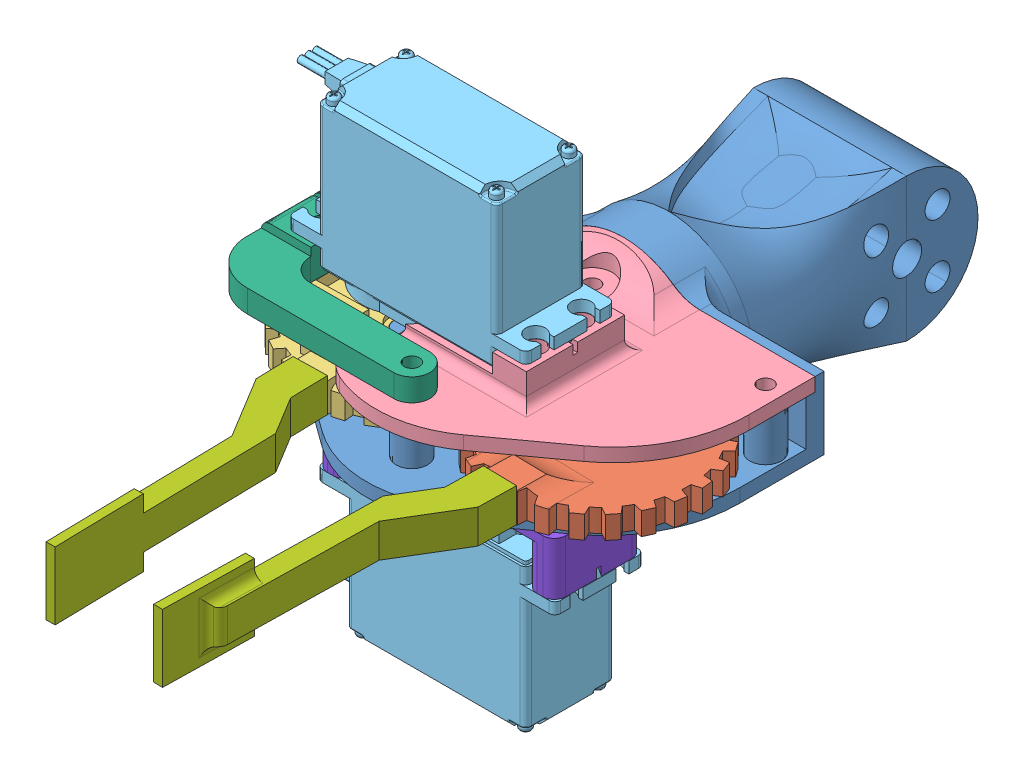
SolidWorks assembly pince, configuration Défaut. Lengths in mm.
Overall size (90.52 95.98 177.73).
10 component instances, 8 part files, 25 mates.
Components (placement in the parent):
- minisegmentServo-1: minisegmentServo [Default] at origin size (85 38 118.68)
- gearnoMot - Copie-2: gearnoMot - Copie [Défaut] at (21.5 5 72.8) x (-0.987503 0 -0.157599) z (-0.157599 0 0.987503) size (43.87 6.5 43.87)
- gearMot-1: gearMot [Défaut] at (-21.5 0 72.8) x (0.999762 0 -0.021829) z (0.021829 0 0.999762) size (43.87 7.5 43.44)
- toppince-1: toppince [Défaut] at (-0.0037 10 45.8) size (85 14.77 55)
- hs-422_sws-1: hs-422_sws [Default] at (-11.213 28.2654 82.706) x (0 0 -1) z (-1 0 0) size (19.81 42.14 58.23)
- supportServo-1: supportServo [Défaut] at (-38.5037 13 52.8) size (46.5 6.78 48)
- bout_pince-1: bout_pince [Défaut] at (21.5017 5 72.7083) x (-0.987503 0 -0.157599) z (-0.157599 0 0.987503) size (11.17 15 72.85)
- bout_pince-2: bout_pince [Défaut] at (-21.5028 2.5 72.6719) x (0.986994 0 -0.160756) z (0.160756 0 0.986994) size (11.17 15 72.85)
- BOTSUPP-1: BOTSUPP [Défaut] at (0 -3 72.8) x (-1 0 0) z (0 0 1) size (52.83 14.74 50)
- hs-422_sws-2: hs-422_sws [Default] at (0.128 -26.2245 67.798) x (0 0 1) z (-1 0 0) size (19.81 42.14 58.23)
Mates (geometry in assembly coordinates):
- Coïncidente1: coincident anti-aligned: plane of minisegmentServo-1 through (-42.5 0 77.8) normal (0 1 0); plane of gearnoMot - Copie-2 through (21.5 0 72.8) normal (0 -1 0)
- Coaxiale3: concentric aligned: cylinder of minisegmentServo-1 through (21.5 11 72.8) axis (0 -1 0) radius 2.49; circle of gearnoMot-2
- Coïncidente2: coincident anti-aligned: plane of minisegmentServo-1 through (-42.5 0 77.8) normal (0 1 0); plane of gearMot-1 through (-21.5 0 72.8) normal (0 -1 0)
- Coaxiale5: concentric aligned: circle of minisegmentServo-1; cylinder of gearMot-1 through (-21.5 5 72.8) axis (0 1 0) radius 2.55
- Coaxiale6: concentric aligned: circle of gearMot-1; circle of hs-422_sws-1
- Contr.Engrenages1: gear = 5 : 5.1 mm: circle of gearnoMot - Copie-2; circle of gearMot-1
- Coaxiale8: concentric anti-aligned: circle of toppince-1; circle of hs-422_sws-1
- Coïncidente7: coincident anti-aligned: plane of toppince-1 through (-0.0037 13 75.8) normal (0 1 0); plane of hs-422_sws-1 through (-11.213 13 82.706) normal (0 -1 0)
- Coaxiale9: concentric aligned: circle of toppince-1; circle of supportServo-1
- Coïncidente9: coincident anti-aligned: plane of toppince-1 through (-0.0037 13 75.8) normal (0 1 0); plane of supportServo-1 through (-0.0037 13 92.8) normal (0 -1 0)
- Coaxiale10: concentric aligned: circle of toppince-1; circle of supportServo-1
- Coïncidente12: coincident anti-aligned: plane of gearnoMot - Copie-2 through (23.4413 1.5 89.3855) normal (0 1 0); plane of bout_pince-1 through (18.9421 1.5 89.3017) normal (0 -1 0)
- Coïncidente13: coincident anti-aligned: plane of gearnoMot - Copie-2 through (21.1917 5 89.3436) normal (-0.018631 0 0.999826); plane of bout_pince-1 through (21.1917 5 89.3436) normal (0.018631 0 -0.999826)
- Coïncidente14: coincident anti-aligned: plane of gearnoMot - Copie-2 through (23.4413 1.5 89.3855) normal (-0.999826 0 -0.018631); plane of bout_pince-1 through (23.4413 1.5 89.3855) normal (0.999826 0 0.018631)
- Coïncidente15: coincident anti-aligned: plane of gearMot-1 through (-23.3891 1.5 89.3552) normal (0 1 0); plane of bout_pince-2 through (-18.8901 1.5 89.257) normal (0 -1 0)
- Coïncidente16: coincident anti-aligned: plane of gearMot-1 through (-18.8901 5 89.257) normal (-0.999762 0 0.021829); plane of bout_pince-2 through (-18.8901 6 89.257) normal (0.999762 0 -0.021829)
- Coïncidente17: coincident anti-aligned: plane of gearMot-1 through (-21.1396 0 89.3061) normal (0.021829 0 0.999762); plane of bout_pince-2 through (-21.1396 2.5 89.3061) normal (-0.021829 0 -0.999762)
- Coïncidente18: coincident anti-aligned: plane of minisegmentServo-1 through (0 0 45.8) normal (0 0 1); plane of toppince-1 through (-42.5037 13 45.8) normal (0 0 -1)
- Coïncidente19: coincident anti-aligned: plane of minisegmentServo-1 through (-42.5 10 47.8) normal (0 1 0); plane of toppince-1 through (-0.0037 10 75.8) normal (0 -1 0)
- Coaxiale11: concentric anti-aligned: circle of minisegmentServo-1; circle of BOTSUPP-1
- Coaxiale12: concentric aligned: circle of minisegmentServo-1; circle of BOTSUPP-1
- Coïncidente20: coincident anti-aligned: plane of minisegmentServo-1 through (-42.5 -3 43.8) normal (0 -1 0); plane of BOTSUPP-1 through (0 -3 52.8) normal (0 1 0)
- Coaxiale13: concentric anti-aligned: circle of BOTSUPP-1; circle of hs-422_sws-2
- Parallèle1: parallel aligned: plane of BOTSUPP-1 through (26.415 -8 67.8) normal (0 0 -1); plane of hs-422_sws-2 through (0.128 -26.2245 67.798) normal (0 0 -1)
- Coïncidente22: coincident anti-aligned: plane of BOTSUPP-1 through (0 -8 72.8) normal (0 -1 0); plane of hs-422_sws-2 through (0.128 -8 87.61) normal (0 1 0)
